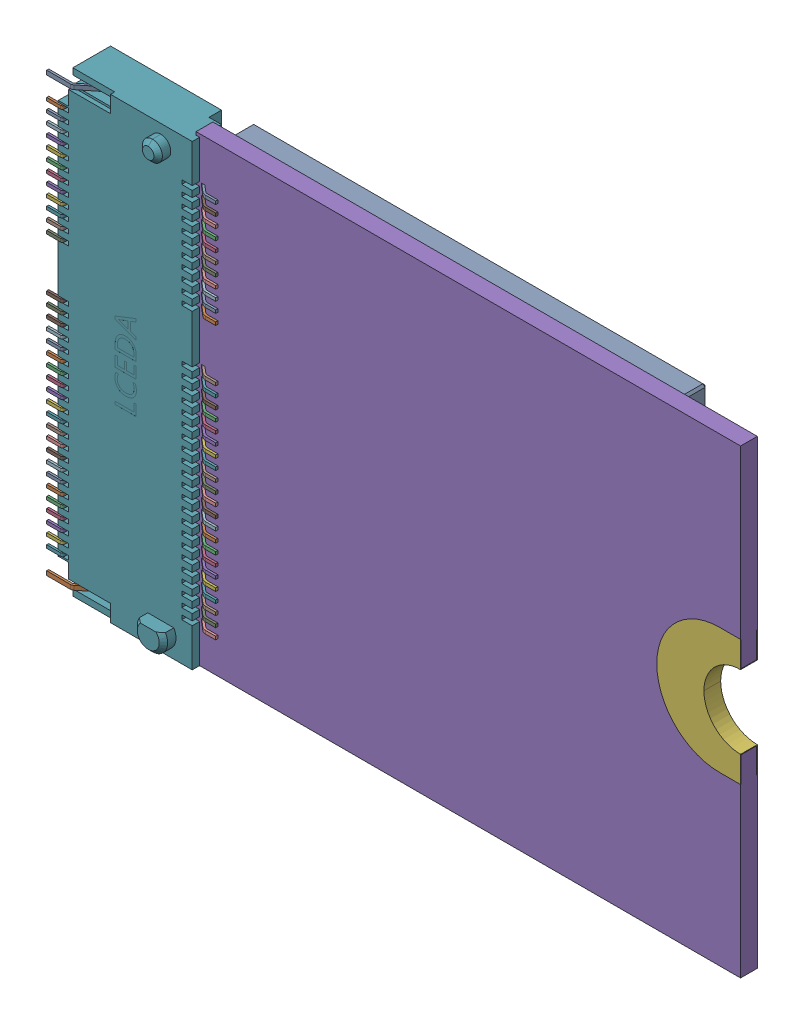
SolidWorks assembly J5, configuration Défaut. Lengths in mm.
Overall size (32.73 22 3.25).
2 component instances, 2 part files, 0 mates.
Components (placement in the parent):
- APCI0147-P001ASLDPRT-1: APCI0147-P001ASLDPRT [Défaut] at (31.337 -33.642 -0.73) x (0 -1 0) z (0 0 -1) size (21.85 8.07 2.6)
- User Library-PCIe_M_2_Key-E_2230_RF-1: User Library-PCIe_M_2_Key-E_2230_RF [Défaut] at (30.1838 -33.568 -2.6818) x (0 1 0) z (0 0 -1) size (22 30 2.3)
